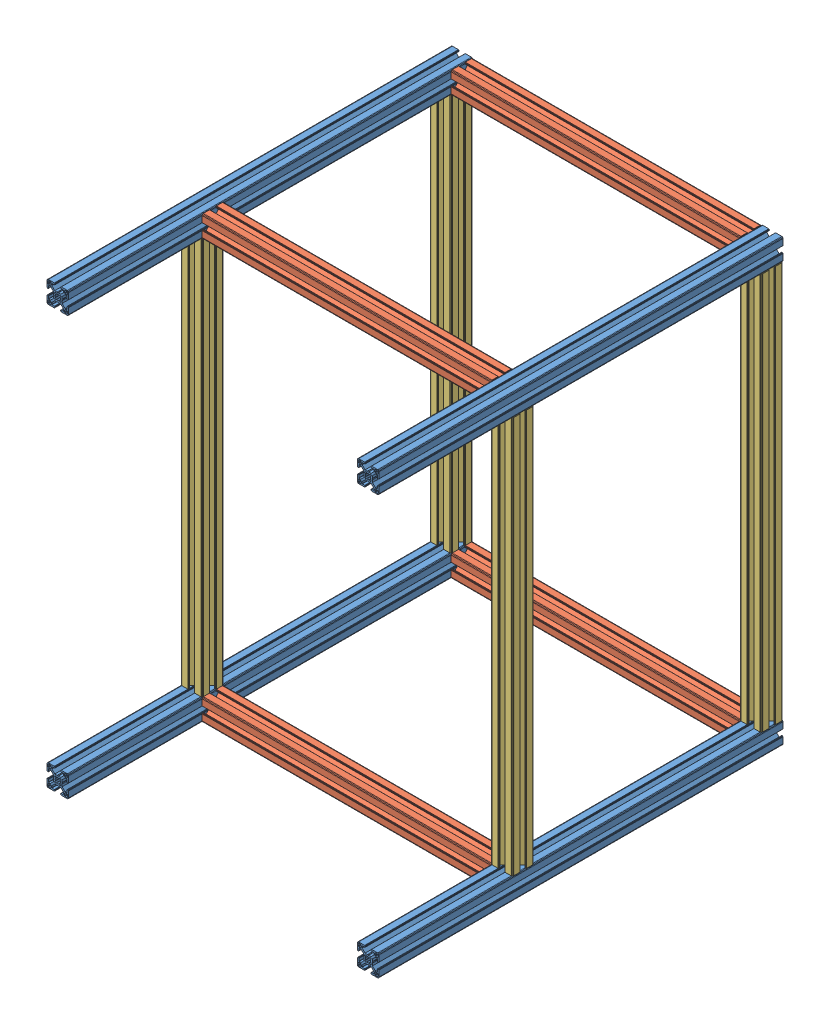
SolidWorks assembly module1_frame_v1.0, configuration Default. Lengths in mm.
Overall size (460 610 560).
12 component instances, 3 part files, 33 mates.
Components (placement in the parent):
- profile_30x30mm_560mm-15: profile_30x30mm_560mm [Default] at origin size (30 30 560)
- profile_30x30mm_560mm-14: profile_30x30mm_560mm [Default] at (430 0 0) size (30 30 560)
- Profile_30x30mm_400mm-19: Profile_30x30mm_400mm [Default] at (430 0 -185) x (0 0 -1) z (1 0 0) size (30 30 400)
- Profile_30x30mm_400mm-18: Profile_30x30mm_400mm [Default] at (430 0 -530) x (0 0 -1) z (1 0 0) size (30 30 400)
- Profile_30x30mm_550mm-16: Profile_30x30mm_550mm [Default] at (0 30 -560) x (1 0 0) z (0 -1 0) size (30 30 550)
- Profile_30x30mm_550mm-17: Profile_30x30mm_550mm [Default] at (0 580 -185) x (1 0 0) z (0 1 0) size (30 30 550)
- Profile_30x30mm_550mm-14: Profile_30x30mm_550mm [Default] at (430 30 -560) x (1 0 0) z (0 -1 0) size (30 30 550)
- profile_30x30mm_560mm-12: profile_30x30mm_560mm [Default] at (430 580 0) size (30 30 560)
- profile_30x30mm_560mm-13: profile_30x30mm_560mm [Default] at (0 580 0) size (30 30 560)
- Profile_30x30mm_400mm-17: Profile_30x30mm_400mm [Default] at (430 580 -560) x (0 1 0) z (1 0 0) size (30 30 400)
- Profile_30x30mm_400mm-16: Profile_30x30mm_400mm [Default] at (30 610 -185) x (0 0 -1) z (-1 0 0) size (30 30 400)
- Profile_30x30mm_550mm-18: Profile_30x30mm_550mm [Default] at (460 580 -215) x (-1 0 0) z (0 1 0) size (30 30 550)
Mates (geometry in assembly coordinates):
- Coincident1: coincident: plane of assembly; plane of assembly; plane of profile_30x30mm_560mm-15 through (0 0 0) normal (0 1 0); plane of profile_30x30mm_560mm-14 through (430 0 0) normal (0 1 0)
- Coincident2: coincident: plane of assembly; plane of assembly; plane of profile_30x30mm_560mm-15 through (0 0 0) normal (0 0 1); plane of profile_30x30mm_560mm-14 through (430 0 0) normal (0 0 1)
- Distance2: distance = 430 mm: plane of assembly; plane of assembly; plane of profile_30x30mm_560mm-14 through (430 0 0) normal (1 0 0); plane of profile_30x30mm_560mm-15 through (0 0 0) normal (1 0 0)
- Coincident4: coincident: plane of ? through (430 0 185) normal (0 1 0); plane of assembly through (0 0 0) normal (0 1 0)
- Coincident5: coincident: plane of profile_30x30mm_560mm-14 through (430 10.25 -560) normal (-1 0 0); plane of ? through (430 0 185) normal (1 0 0)
- Coincident44: coincident: plane of ? through (430 0 185) normal (0 0 -1); plane of ? through (2 30 185) normal (0 0 1)
- Coincident7: coincident: plane of assembly through (0 0 0) normal (0 1 0); plane of Profile_30x30mm_400mm-18 through (430 0 -530) normal (0 1 0); plane of assembly
- Distance3: distance = 530 mm: plane of assembly through (0 0 0) normal (0 0 1); plane of Profile_30x30mm_400mm-18 through (430 0 -530) normal (0 0 -1); plane of assembly
- Coincident9: coincident: plane of assembly; plane of assembly; plane of profile_30x30mm_560mm-14 through (430 28 -560) normal (-1 0 0); plane of Profile_30x30mm_400mm-18 through (430 0 -530) normal (1 0 0)
- Coincident10: coincident: plane of assembly; plane of assembly; plane of profile_30x30mm_560mm-15 through (28 30 -560) normal (0 1 0); plane of Profile_30x30mm_550mm-16 through (0 30 -560) normal (0 -1 0)
- Coincident11: coincident: plane of assembly; plane of assembly; plane of profile_30x30mm_560mm-15 through (0 0 -560) normal (0 0 -1); plane of Profile_30x30mm_550mm-16 through (0 30 -560) normal (0 0 1)
- Coincident12: coincident: plane of assembly; plane of assembly; plane of profile_30x30mm_560mm-15 through (0 10.25 -560) normal (-1 0 0); plane of Profile_30x30mm_550mm-16 through (0 580 -549.75) normal (-1 0 0)
- Coincident15: coincident: plane of Profile_30x30mm_550mm-16 through (0 30 -560) normal (1 0 0); plane of ? through (0 580 185) normal (1 0 0)
- Distance6: distance = 550 mm: plane of assembly; plane of assembly; plane of Profile_30x30mm_550mm-17 through (0 580 -185) normal (0 1 0); plane of Profile_30x30mm_550mm-16 through (0 30 -560) normal (0 -1 0)
- Coincident21: coincident: plane of assembly; plane of assembly; plane of profile_30x30mm_560mm-14 through (458 30 -560) normal (0 1 0); plane of Profile_30x30mm_550mm-14 through (430 30 -560) normal (0 -1 0)
- Coincident22: coincident: plane of assembly; plane of assembly; plane of Profile_30x30mm_400mm-18 through (30 2 -560) normal (0 0 -1); plane of Profile_30x30mm_550mm-14 through (430 30 -560) normal (0 0 1)
- Coincident23: coincident: plane of assembly; plane of assembly; plane of profile_30x30mm_560mm-14 through (460 19.75 -560) normal (1 0 0); plane of Profile_30x30mm_550mm-14 through (460 580 -558) normal (1 0 0)
- Coincident24: coincident: plane of assembly; plane of assembly; plane of Profile_30x30mm_550mm-14 through (430 580 -560) normal (0 1 0); plane of profile_30x30mm_560mm-12 through (449.75 580 -560) normal (0 -1 0)
- Coincident25: coincident: plane of assembly; plane of assembly; plane of Profile_30x30mm_550mm-14 through (460 580 -540.25) normal (1 0 0); plane of profile_30x30mm_560mm-12 through (460 582 -560) normal (1 0 0)
- Coincident26: coincident: plane of assembly; plane of assembly; plane of Profile_30x30mm_550mm-14 through (432 580 -560) normal (0 0 -1); plane of profile_30x30mm_560mm-12 through (430 580 -560) normal (0 0 -1)
- Coincident27: coincident: plane of assembly; plane of assembly; plane of Profile_30x30mm_550mm-16 through (0 580 -560) normal (0 1 0); plane of profile_30x30mm_560mm-13 through (19.75 580 -560) normal (0 -1 0)
- Coincident28: coincident: plane of assembly; plane of assembly; plane of Profile_30x30mm_550mm-16 through (2 580 -560) normal (0 0 -1); plane of profile_30x30mm_560mm-13 through (0 580 -560) normal (0 0 -1)
- Coincident29: coincident: plane of assembly; plane of assembly; plane of Profile_30x30mm_550mm-16 through (0 580 -532) normal (-1 0 0); plane of profile_30x30mm_560mm-13 through (0 590.25 -560) normal (-1 0 0)
- Coincident30: coincident: plane of assembly; plane of assembly; plane of profile_30x30mm_560mm-13 through (30 599.75 -560) normal (1 0 0); plane of Profile_30x30mm_400mm-17 through (30 580 -560) normal (-1 0 0)
- Coincident31: coincident: plane of assembly; plane of assembly; plane of profile_30x30mm_560mm-13 through (0 580 -560) normal (0 0 -1); plane of Profile_30x30mm_400mm-17 through (30 582 -560) normal (0 0 -1)
- Coincident32: coincident: plane of assembly; plane of assembly; plane of profile_30x30mm_560mm-12 through (440.25 610 -560) normal (0 1 0); plane of Profile_30x30mm_400mm-17 through (30 610 -558) normal (0 1 0)
- Coincident36: coincident: plane of profile_30x30mm_560mm-13 through (30 599.75 -560) normal (1 0 0); plane of ? through (30 610 185) normal (-1 0 0)
- Coincident37: coincident: plane of profile_30x30mm_560mm-13 through (10.25 610 -560) normal (0 1 0); plane of ? through (430 610 165.25) normal (0 1 0)
- Distance9: distance = 185 mm: plane of assembly; plane of assembly; plane of profile_30x30mm_560mm-12 through (430 580 0) normal (0 0 1); plane of Profile_30x30mm_400mm-16 through (430 582 -185) normal (0 0 1)
- Coincident43: coincident: plane of ? through (2 30 185) normal (0 0 1); plane of ? through (430 582 185) normal (0 0 1)
- Coincident61: coincident: plane of ? through (2 30 185) normal (0 0 1); plane of ? through (432 30 185) normal (0 0 1)
- Coincident62: coincident: plane of profile_30x30mm_560mm-14 through (458 30 -560) normal (0 1 0); plane of ? through (460 30 155) normal (0 -1 0)
- Coincident63: coincident: plane of profile_30x30mm_560mm-14 through (460 19.75 -560) normal (1 0 0); plane of ? through (460 30 183) normal (1 0 0)
